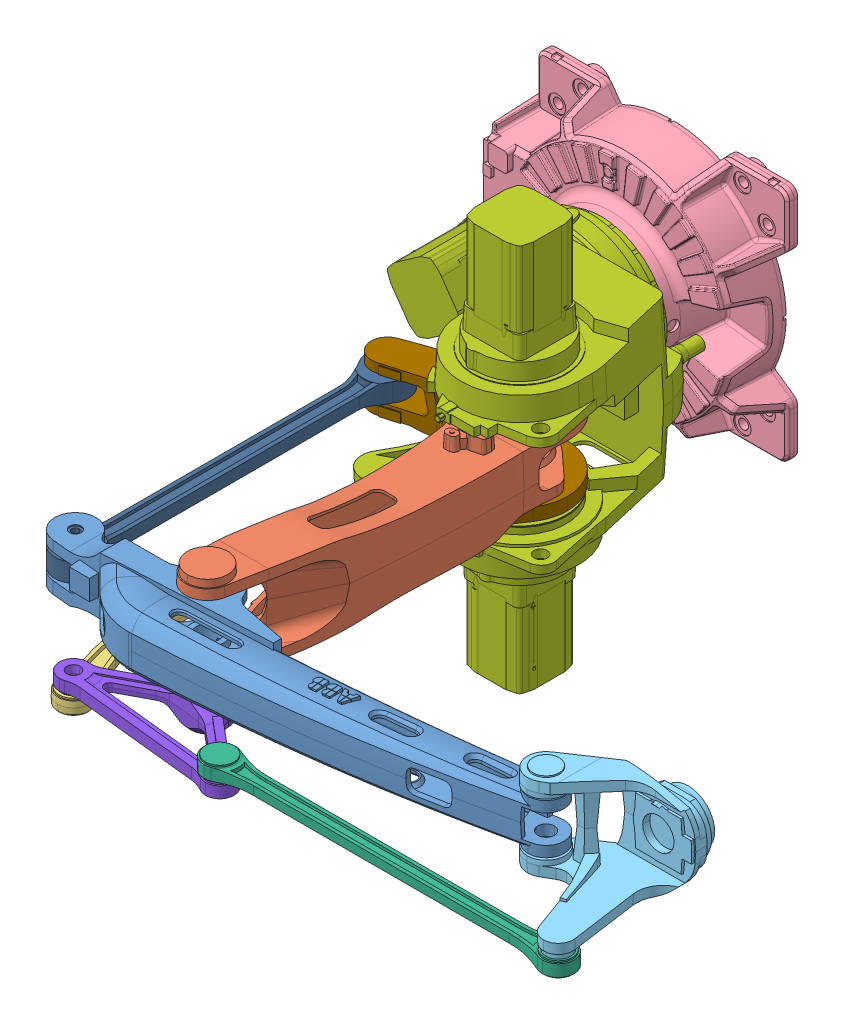
SolidWorks assembly IRB-460-SW, configuration 默认. Lengths in mm.
Overall size (2006.55 1174.02 1974.28).
11 component instances, 10 part files, 0 mates.
Components (placement in the parent):
- IRB-460^IRB-460-SW-1: IRB-460^IRB-460-SW [默认] at origin size (2006.55 1174.02 1974.28) (virtual)
  - Upper arm^IRB-460_IRB-460-SW-1: Upper arm^IRB-460_IRB-460-SW [默认] at origin size (1542.5 204.74 287.36) (virtual)
  - Lower arm^IRB-460_IRB-460-SW-1: Lower arm^IRB-460_IRB-460-SW [默认] at origin size (314.03 294 1159) (virtual)
  - lower link^IRB-460_IRB-460-SW-1: lower link^IRB-460_IRB-460-SW [默认] at origin size (171.35 51.83 1041) (virtual)
  - Foot^IRB-460_IRB-460-SW-1: Foot^IRB-460_IRB-460-SW [默认] at (-51.2795 15.6414 -31.2679) size (776.57 720.03 285.22) (virtual)
  - Tilt^IRB-460_IRB-460-SW-1: Tilt^IRB-460_IRB-460-SW [默认] at origin size (382.5 312 455.34) (virtual)
  - upper link^IRB-460_IRB-460-SW-1: upper link^IRB-460_IRB-460-SW [默认] at origin size (1121 45 187.44) (virtual)
  - swing^IRB-460_IRB-460-SW-1: swing^IRB-460_IRB-460-SW [默认] at origin size (752.53 1174.02 752) (virtual)
  - link plate^IRB-460_IRB-460-SW-1: link plate^IRB-460_IRB-460-SW [默认] at origin size (581.95 139 326.83) (virtual)
  - P arm^IRB-460_IRB-460-SW-1: P arm^IRB-460_IRB-460-SW [默认] at origin size (595 187 361.79) (virtual)
  - P link^IRB-460_IRB-460-SW-1: P link^IRB-460_IRB-460-SW [默认] at origin size (135.71 135 1070) (virtual)
